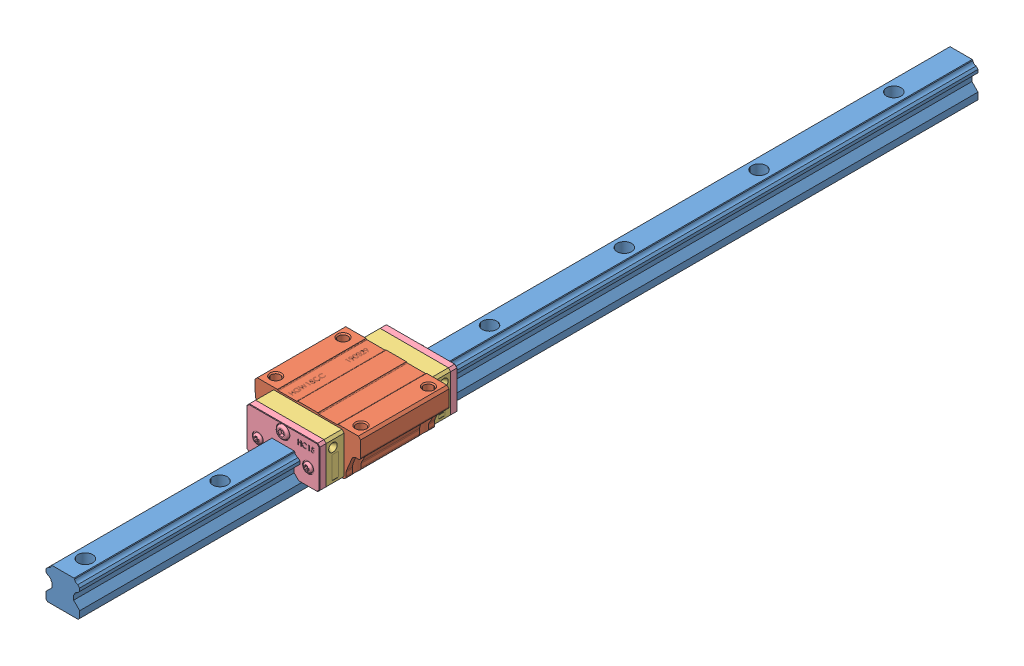
SolidWorks assembly HGRW15-, configuration По умолчанию. Lengths in mm.
Overall size (47 24 400).
7 component instances, 4 part files, 2 mates.
Components (placement in the parent):
- HGR15-1: HGR15 [По умолчанию] at (-39.1535 -2.3252 -166.0205) size (15 15 400)
- HGW15CC-1: HGW15CC [По умолчанию] at (-39.1535 1.9748 85.5055) size (47 19.7 63.41)
  - HGW15CC1-1: HGW15CC1 [По умолчанию] at origin size (47 19.7 39.4)
  - HGW15CC2-1: HGW15CC2 [По умолчанию] at (0 0 39.4) size (32.4 18.7 8)
  - HGW15CC2-2: HGW15CC2 [По умолчанию] x (-1 0 0) z (0 0 -1) size (32.4 18.7 8)
  - HGW15CC3-1: HGW15CC3 [По умолчанию] at (0 0 -8) x (-1 0 0) z (0 0 -1) size (32.4 18.7 4)
  - HGW15CC3-2: HGW15CC3 [По умолчанию] at (0 0 47.4) size (32.4 18.7 4)
Mates (geometry in assembly coordinates):
- Концентричный1: concentric aligned: cylinder of HGR15R600-1 through (-45.975 6.3115 233.9795) axis (0 0 -1) radius 1.63; cylinder of HGW15CCZ0C-1/HGW15CCZ0C_2-1 through (-45.975 6.3115 132.9055) axis (0 0 -1) radius 1.63
- Концентричный2: concentric aligned: cylinder of HGR15R600-1 through (-32.332 6.3115 233.9795) axis (0 0 -1) radius 1.63; cylinder of HGW15CCZ0C-1/HGW15CCZ0C_2-1 through (-32.332 6.3115 132.9055) axis (0 0 -1) radius 1.63
